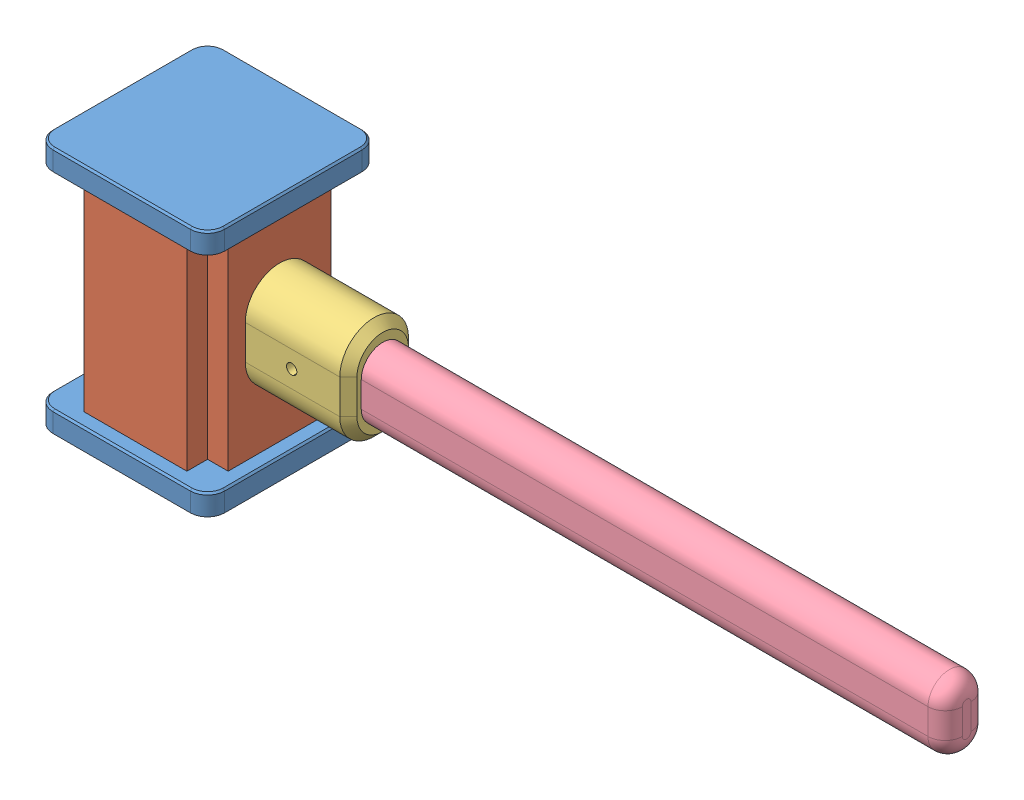
SolidWorks assembly E59, configuration Predeterminado. Lengths in mm.
Overall size (342 144 100).
8 component instances, 4 part files, 17 mates.
Components (placement in the parent):
- P59.1-1: P59.1 [Predeterminado] at origin size (100 12 100)
- P59.2-1: P59.2 [Predeterminado] at (0 72 -30) x (0 0 -1) z (1 0 0) size (12 120 60)
- P59.2-2: P59.2 [Predeterminado] at (30 72 0) size (12 120 60)
- P59.2-3: P59.2 [Predeterminado] at (-42 72 0) size (12 120 60)
- P59.2-4: P59.2 [Predeterminado] at (0 72 42) x (0 0 -1) z (1 0 0) size (12 120 60)
- P59.1-4: P59.1 [Predeterminado] at (0 132 0) size (100 12 100)
- P59.3-1: P59.3 [Predeterminado] at (42 79.5 0) x (0 -1 0) z (0 0 1) size (60 60 40)
- P59.4-1: P59.4 [Predeterminado] at (42 64.5 0) x (1 0 0) z (0 -1 0) size (400 25 40)
Mates (geometry in assembly coordinates):
- Coincidente1: coordinate: point of P59.1-1
- Coincidente15: coincident anti-aligned: plane of P59.1-1 through (40 12 -40) normal (0 1 0); plane of P59.2-1 through (30 12 -42) normal (0 -1 0)
- Coincidente17: coincident anti-aligned: plane of P59.1-1 through (40 12 -40) normal (0 1 0); plane of P59.2-3 through (-30 12 30) normal (0 -1 0)
- Coincidente19: coincident anti-aligned: plane of P59.1-1 through (40 12 -40) normal (0 1 0); plane of P59.2-4 through (30 12 30) normal (0 -1 0)
- Coincidente20: coincident: point of P59.2-3; point of P59.2-4
- Coincidente21: coincident anti-aligned: plane of P59.1-1 through (40 12 -40) normal (0 1 0); plane of P59.2-2 through (42 12 30) normal (0 -1 0)
- Coincidente23: coincident: point of P59.2-1; point of P59.2-2
- Coincidente24: coincident: point of P59.2-1; point of P59.2-3
- Coincidente31: coincident: unknown of P59.2-1
- Coincidente32: coincident: unknown of P59.2-4
- Coincidente33: coincident: unknown of P59.2-3
- Coincidente35: coincident aligned: line of P59.2-2 through (30 132 30) axis (0 -1 0); line of P59.2-4 through (30 132 30) axis (0 -1 0)
- Coincidente42: coincident anti-aligned: plane of P59.2-2 through (42 72 0) normal (1 0 0); plane of P59.3-1 through (42 82 0) normal (-1 0 0)
- Coincidente43: coincident: moEndPointRef_w of P59.3-1
- Coincidente45: coincident: unknown of P59.3-1
- Coincidente46: coincident: plane of P59.3-1 through (102 79.5 12.5) normal (0 0 -1); plane of P59.4-1 through (797.8366 173.2549 12.5) normal (0 0 1)
- Coincidente48: coincident aligned: circle of P59.3-1; circle of P59.4-1
